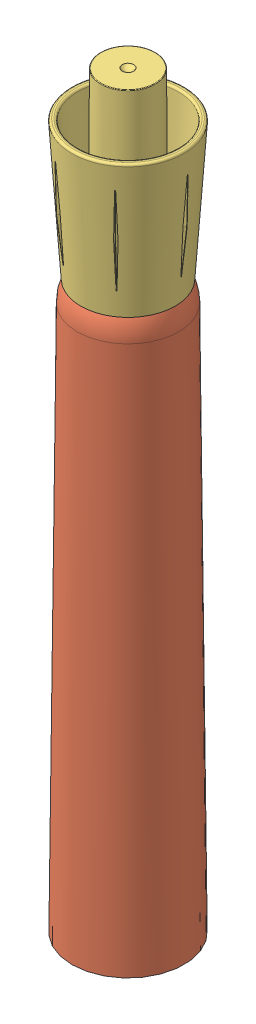
SolidWorks assembly EMF, configuration Default. Lengths in mm.
Overall size (22.53 123.53 22.53).
5 component instances, 5 part files, 9 mates.
Components (placement in the parent):
- tip-1: tip [Default] at (-28.5306 58.9734 41.2191) x (-0.333247 0 -0.942839) z (0.942839 0 -0.333247) size (6.14 40.54 3.7)
- EARTH-1: EARTH [Default] at (-26.7419 -40.0322 40.7284) size (18.51 113.74 18.51)
- Expo Marker Cap-1: Expo Marker Cap [Default] at (-26.7419 53.3423 40.7284) x (0.995537 0 -0.094372) z (0.094372 0 0.995537) size (18.55 30.16 18.55)
- marker bottom-1: marker bottom [Default] at (-26.7419 -32.1122 40.7284) x (0.885678 0 -0.464299) z (-0.464299 0 -0.885678) size (16.69 10.84 16.69)
- ink-1: ink [Default] at (-26.7419 50.3214 40.7284) x (0.333247 0 0.942839) z (0.942839 0 -0.333247) size (12.79 80.99 12.79)
Mates (geometry in assembly coordinates):
- Concentric1: concentric aligned: cone of EARTH-1 through (-26.7419 49.9678 40.7284) axis (0 1 0); cylinder of marker bottom-1 through (-26.7419 -40.0322 40.7284) axis (0 1 0) radius 8.345
- Coincident1: coincident aligned: plane of EARTH-1 through (-26.7419 -40.0322 40.7284) normal (0 -1 0); plane of marker bottom-1 through (-26.7419 -40.0322 40.7284) normal (0 -1 0)
- Concentric2: concentric aligned: cone of EARTH-1 through (-26.7419 56.2984 40.7284) axis (0 1 0); cone of Expo Marker Cap-1 through (-26.7419 82.5023 40.7284) axis (0 1 0)
- Coincident2: coincident anti-aligned: plane of tip-1 through (-23.9746 77.8214 43.0064) normal (0.333247 0 0.942839); plane of ink-1 through (-27.4631 41.8214 44.2394) normal (-0.333247 0 -0.942839)
- Coincident3: coincident anti-aligned: plane of tip-1 through (-25.0421 58.9734 39.986) normal (0.942839 0 -0.333247); plane of ink-1 through (-26.0207 41.8214 37.2174) normal (-0.942839 0 0.333247)
- Concentric4: concentric aligned: cone of EARTH-1 through (-26.7419 49.9678 40.7284) axis (0 1 0); cylinder of ink-1 through (-26.7419 -30.6686 40.7284) axis (0 1 0) radius 6.395
- Coincident9: coincident anti-aligned: plane of tip-1 through (26.8575 61.6844 18.5275) normal (0 -1 0); plane of EARTH-1 through (-23.3055 61.6844 40.7284) normal (0 1 0)
- Coincident11: coincident anti-aligned: line of tip-1 through (-24.8231 41.8214 43.3063) axis (-0.942839 0 0.333247); line of ink-1 through (-27.4631 41.8214 44.2394) axis (0.942839 0 -0.333247)
- Tangent1: tangent: torus of EARTH-1; circle of Expo Marker Cap-1
